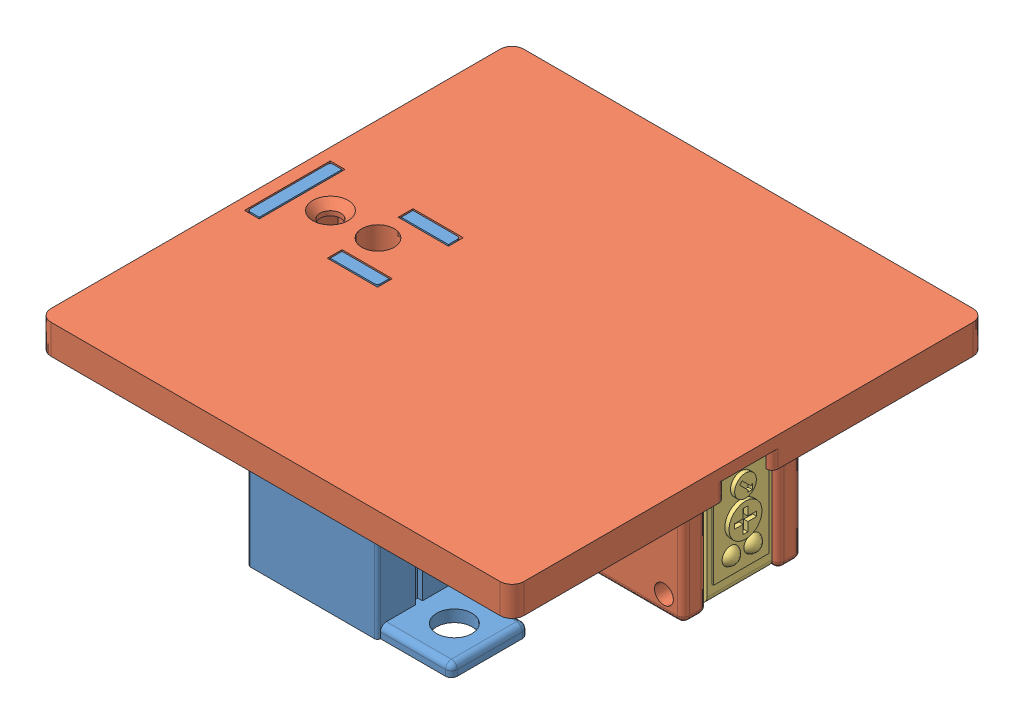
SolidWorks assembly Pilier_top_sick, configuration Default. Lengths in mm.
Overall size (80 52 80).
4 component instances, 3 part files, 3 mates.
Components (placement in the parent):
- Pilier-1: Pilier [Default] at (-7.3604 -4.447 58.7428) size (34 52 14)
- Plaque_top_SICK-1: Plaque_top_SICK [Default] at (-9.6075 42.553 91.7428) size (80 21 80)
  - Plaque_top-2: Plaque_top [Default] at origin size (80 21 80)
  - SICK WL100-N4439-Bestell-Nr_6028604(0)-1-1: SICK WL100-N4439-Bestell-Nr_6028604(0)-1 [Default] at (50.3 -13 -45.5) x (0 1 0) z (0 0 -1) size (20 42.65 11)
Mates (geometry in assembly coordinates):
- Coincident1: coincident aligned: plane of Pilier-1 through (-7.3604 47.553 58.7428) normal (0 1 0); plane of Plaque_top_SICK-1/Plaque_top-2 through (-9.6075 47.553 91.7428) normal (0 1 0)
- Concentric1: concentric aligned: circle of Pilier-1; circle of Plaque_top_SICK-1/Plaque_top-2
- Parallel1: parallel aligned: line of Pilier-1 through (-7.3604 47.553 45.2428) axis (0 0 1); line of Plaque_top_SICK-1/Plaque_top-2 through (-7.6075 47.553 44.4928) axis (0 0 1)
